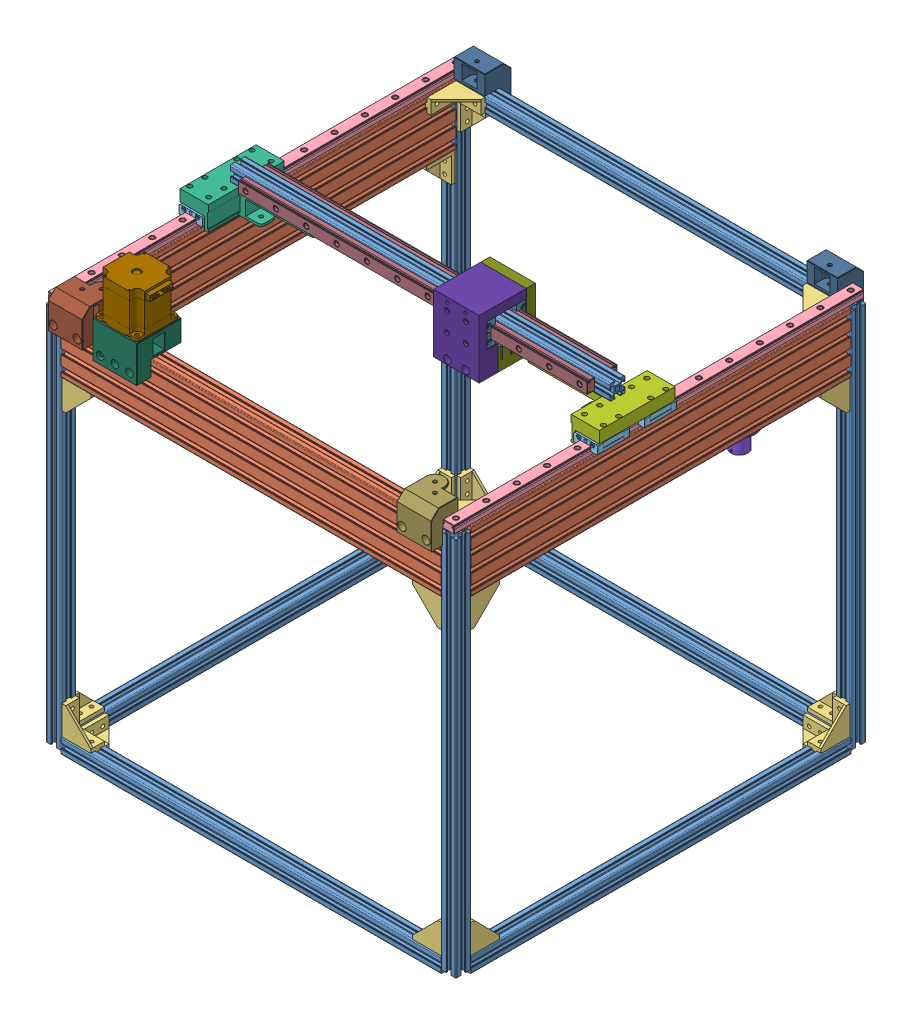
SolidWorks assembly full_assem, configuration Default. Lengths in mm.
Overall size (552 591.02 574.21).
62 component instances, 19 part files, 212 mates.
Components (placement in the parent):
- extrusion_2020_500mm-1: extrusion_2020_500mm [Default] at (57.1895 57.3768 420.5432) size (20 500 20)
- extrusion_2020_500mm-2: extrusion_2020_500mm [Default] at (567.1895 62.3768 420.5432) x (0 1 0) z (0 0 1) size (20 500 20)
- extrusion_2020_500mm-3: extrusion_2020_500mm [Default] at (577.1895 57.3768 420.5432) size (20 500 20)
- extrusion_2020_500mm-6: extrusion_2020_500mm [Default] at (57.1895 57.3768 -99.4568) size (20 500 20)
- extrusion_2020_500mm-7: extrusion_2020_500mm [Default] at (57.1895 62.3768 -89.4568) x (1 0 0) z (0 -1 0) size (20 500 20)
- extrusion_2020_500mm-9: extrusion_2020_500mm [Default] at (577.1895 57.3768 -99.4568) size (20 500 20)
- extrusion_2020_500mm-10: extrusion_2020_500mm [Default] at (577.1895 62.3768 -89.4568) x (1 0 0) z (0 -1 0) size (20 500 20)
- extrusion_2020_500mm-11: extrusion_2020_500mm [Default] at (67.1895 552.3768 -99.4568) x (0 -1 0) z (0 0 1) size (20 500 20)
- extrusion_2020_500mm-12: extrusion_2020_500mm [Default] at (567.1895 62.3768 -99.4568) x (0 1 0) z (0 0 1) size (20 500 20)
- extrusion_2080_500mm-1: extrusion_2080_500mm [Default] at (577.1895 492.3768 -589.4568) size (20 80 500)
- extrusion_2080_500mm-2: extrusion_2080_500mm [Default] at (57.1895 492.3768 -589.4568) size (20 80 500)
- extrusion_2080_500mm-3: extrusion_2080_500mm [Default] at (1067.1895 492.3768 420.5432) x (0 0 1) z (-1 0 0) size (20 80 500)
- corner_2020_38mm-1: corner_2020_38mm [Default] at (567.1895 53.3768 410.5432) x (1 0 0) z (0 1 0) size (40 40 18)
- corner_2020_38mm-3: corner_2020_38mm [Default] at (67.1895 53.3768 410.5432) x (0 0 1) z (0 1 0) size (40 40 18)
- corner_2020_38mm-4: corner_2020_38mm [Default] at (67.1895 53.3768 -89.4568) x (-1 0 0) z (0 1 0) size (40 40 18)
- corner_2020_38mm-5: corner_2020_38mm [Default] at (567.1895 53.3768 -89.4568) x (0 0 -1) z (0 1 0) size (40 40 18)
- corner_2020_38mm-7: corner_2020_38mm [Default] at (48.1895 72.3768 410.5432) x (0 -1 0) z (1 0 0) size (40 40 18)
- corner_2020_38mm-9: corner_2020_38mm [Default] at (48.1895 482.3768 410.5432) x (0 0 1) z (1 0 0) size (40 40 18)
- corner_2020_38mm-10: corner_2020_38mm [Default] at (48.1895 482.3768 -89.4568) x (0 1 0) z (1 0 0) size (40 40 18)
- corner_2020_38mm-11: corner_2020_38mm [Default] at (48.1895 72.3768 -89.4568) x (0 0 -1) z (1 0 0) size (40 40 18)
- corner_2020_38mm-13: corner_2020_38mm [Default] at (67.1895 72.3768 -108.4568) x (0 -1 0) z (0 0 1) size (40 40 18)
- corner_2020_38mm-15: corner_2020_38mm [Default] at (567.1895 72.3768 -108.4568) size (40 40 18)
- corner_2020_38mm-16: corner_2020_38mm [Default] at (567.1895 542.3768 -108.4568) x (0 1 0) z (0 0 1) size (40 40 18)
- corner_2020_38mm-17: corner_2020_38mm [Default] at (67.1895 542.3768 -108.4568) x (-1 0 0) z (0 0 1) size (40 40 18)
- corner_2020_38mm-19: corner_2020_38mm [Default] at (67.1895 561.3768 -89.4568) x (0 0 -1) z (0 -1 0) size (40 40 18)
- corner_2020_38mm-21: corner_2020_38mm [Default] at (567.1895 561.3768 -89.4568) x (1 0 0) z (0 -1 0) size (40 40 18)
- corner_2020_38mm-22: corner_2020_38mm [Default] at (567.1895 561.3768 410.5432) x (0 0 1) z (0 -1 0) size (40 40 18)
- corner_2020_38mm-23: corner_2020_38mm [Default] at (67.1895 561.3768 410.5432) x (-1 0 0) z (0 -1 0) size (40 40 18)
- corner_2020_38mm-25: corner_2020_38mm [Default] at (67.1895 482.3768 429.5432) x (0 1 0) z (0 0 -1) size (40 40 18)
- corner_2020_38mm-27: corner_2020_38mm [Default] at (567.1895 482.3768 429.5432) x (1 0 0) z (0 0 -1) size (40 40 18)
- corner_2020_38mm-28: corner_2020_38mm [Default] at (567.1895 72.3768 429.5432) x (0 -1 0) z (0 0 -1) size (40 40 18)
- corner_2020_38mm-29: corner_2020_38mm [Default] at (67.1895 72.3768 429.5432) x (-1 0 0) z (0 0 -1) size (40 40 18)
- corner_2020_38mm-31: corner_2020_38mm [Default] at (586.1895 72.3768 -89.4568) x (0 -1 0) z (-1 0 0) size (40 40 18)
- corner_2020_38mm-33: corner_2020_38mm [Default] at (586.1895 72.3768 410.5432) x (0 0 1) z (-1 0 0) size (40 40 18)
- corner_2020_38mm-34: corner_2020_38mm [Default] at (586.1895 482.3768 410.5432) x (0 1 0) z (-1 0 0) size (40 40 18)
- corner_2020_38mm-35: corner_2020_38mm [Default] at (586.1895 482.3768 -89.4568) x (0 0 -1) z (-1 0 0) size (40 40 18)
- rail_mgn15_540mm-1: rail_mgn15_540mm [Default] at (57.1895 562.3768 -119.4568) x (0 0 1) z (0 1 0) size (540 15 10)
- rail_mgn15_540mm-2: rail_mgn15_540mm [Default] at (577.1895 562.3768 -119.4568) x (0 0 1) z (0 1 0) size (540 15 10)
- carriage_mgn15c-1: carriage_mgn15c [Default] at (577.1895 562.3768 212.3583) x (0 0 1) z (0 1 0) size (42.1 32 12)
- carriage_mgn15c-2: carriage_mgn15c [Default] at (57.1895 562.3768 212.3583) x (0 0 1) z (0 1 0) size (42.1 32 12)
- bed_400mm-1: bed_400mm [Default] at (317.1895 407.8394 160.5432) size (400 9.53 400) (hidden)
- extrusion_2020_500mm-14: extrusion_2020_500mm [Default] at (67.1895 603.8768 197.8083) x (0 -1 0) z (0 0 1) size (20 500 20)
- carriage_mgn15c-4: carriage_mgn15c [Default] at (577.1895 562.3768 150.2583) x (0 0 1) z (0 1 0) size (42.1 32 12)
- carriage_mgn15c-5: carriage_mgn15c [Default] at (57.1895 562.3768 183.2583) x (0 0 -1) z (0 1 0) size (42.1 32 12)
- brakcet_xy_right-1: brakcet_xy_right [Default] at (41.1895 578.3768 147.8083) x (0 0 1) z (-1 0 0) size (100 31.5 137)
- brakcet_xy_left-1: brakcet_xy_left [Default] at (610.8271 564.0049 199.7363) x (0 0 1) z (-1 0 0) size (100 31.5 137)
- corner_2020_38mm-36: corner_2020_38mm [Default] at (567.1895 483.3768 410.5432) x (1 0 0) z (0 1 0) size (40 40 18)
- corner_2020_38mm-38: corner_2020_38mm [Default] at (67.1895 483.3768 410.5432) x (0 0 1) z (0 1 0) size (40 40 18)
- ballnut_sfu1204-1: ballnut_sfu1204 [Default] at (456.6258 344.4354 -73.2967) size (42.44 40.17 30.1)
- belt_master_model-1: belt_master_model [Default] at (561.1895 566.3768 -109.4568) x (-1 0 0) z (0 0 -1) size (488 0 540)
- motor_stepper_nema23_57mm-2: motor_stepper_nema23_57mm [По умолчанию] at (157.0122 590.3768 420.5432) x (0 0 1) z (0 1 0) size (55 60 79.15)
- belt_end_right-1: belt_end_right [Default] at (84.9257 562.3768 -99.4568) x (-1 0 0) z (0 0 -1) size (40.48 45 35)
- belt_end_right-2: belt_end_right [Default] at (549.4533 562.3768 -99.4568) x (-1 0 0) z (0 0 -1) size (40.48 45 35)
- belt_corner_right-1: belt_corner_right [Default] at (84.9257 562.3768 420.5432) size (45.48 45 50.24)
- belt_corner_left-2: belt_corner_left [Default] at (498.9733 562.3768 420.5432) size (45.48 45 50.24)
- rail_mgn15_460mm-1: rail_mgn15_460mm [Default] at (557.1895 603.8768 187.8083) x (-1 0 0) z (0 0 -1) size (460 15 10)
- carriage_mgn15h-1: carriage_mgn15h [Default] at (415.5036 603.8768 187.8083) x (-1 0 0) z (0 0 -1) size (58.8 32 12)
- stepper_mount_nema23-1: stepper_mount_nema23 [Default] at (157.0122 562.3768 420.5432) x (1 0 0) z (0 1 0) size (58.42 58.42 48)
- belt_mount-1: belt_mount [Default] at (391.0036 593.3768 159.8083) size (60 77 49)
- rail_mgn15_460mm-2: rail_mgn15_460mm [Default] at (77.1895 603.8768 207.8083) size (460 15 10)
- carriage_mgn15h-2: carriage_mgn15h [Default] at (366.5036 603.8768 207.8083) size (58.8 32 12)
- carriage_back-1: carriage_back [Default] at (421.0036 554.8768 233.8083) x (-1 0 0) z (0 -1 0) size (60 62 77)
Mates (geometry in assembly coordinates):
- Distance13: distance = 15 mm anti-aligned: plane of extrusion_2020_500mm-1 through (57.1895 57.3768 420.5432) normal (0 -1 0); plane of extrusion_2020_500mm-2 through (-239.8105 72.3768 420.5432) normal (0 1 0)
- Coincident2: coincident aligned: plane of extrusion_2020_500mm-1 through (57.1895 864.3768 430.5432) normal (0 0 1); plane of extrusion_2020_500mm-2 through (-239.8105 62.3768 430.5432) normal (0 0 1)
- Coincident3: coincident anti-aligned: plane of extrusion_2020_500mm-1 through (67.1895 864.3768 420.5432) normal (1 0 0); plane of extrusion_2020_500mm-2 through (67.1895 62.3768 420.5432) normal (-1 0 0)
- Coincident4: coincident aligned: plane of extrusion_2020_500mm-2 through (-239.8105 62.3768 430.5432) normal (0 0 1); plane of extrusion_2020_500mm-3 through (577.1895 864.3768 430.5432) normal (0 0 1)
- Coincident5: coincident anti-aligned: plane of extrusion_2020_500mm-2 through (567.1895 62.3768 420.5432) normal (1 0 0); plane of extrusion_2020_500mm-3 through (567.1895 864.3768 420.5432) normal (-1 0 0)
- Distance16: distance = 15 mm anti-aligned: plane of extrusion_2020_500mm-2 through (-239.8105 72.3768 420.5432) normal (0 1 0); plane of extrusion_2020_500mm-3 through (577.1895 57.3768 420.5432) normal (0 -1 0)
- Coincident8: coincident anti-aligned: plane of extrusion_2020_500mm-1 through (67.1895 864.3768 420.5432) normal (1 0 0); plane of extrusion_2020_500mm-4 through (67.1895 552.3768 420.5432) normal (-1 0 0)
- Coincident9: coincident aligned: plane of extrusion_2020_500mm-1 through (57.1895 864.3768 430.5432) normal (0 0 1); plane of extrusion_2020_500mm-4 through (-239.8105 552.3768 430.5432) normal (0 0 1)
- Coincident10: coincident anti-aligned: plane of extrusion_2020_500mm-4 through (-239.8105 552.3768 410.5432) normal (0 0 -1); plane of extrusion_2020_500mm-5 through (57.1895 567.3768 410.5432) normal (0 0 1)
- Coincident12: coincident aligned: plane of extrusion_2020_500mm-4 through (-239.8105 562.3768 420.5432) normal (0 1 0); plane of extrusion_2020_500mm-5 through (57.1895 577.3768 717.5432) normal (0 1 0)
- Coincident13: coincident anti-aligned: plane of extrusion_2020_500mm-5 through (57.1895 567.3768 -89.4568) normal (0 0 -1); plane of extrusion_2020_500mm-6 through (57.1895 864.3768 -89.4568) normal (0 0 1)
- Coincident14: coincident anti-aligned: plane of extrusion_2020_500mm-5 through (57.1895 557.3768 717.5432) normal (0 -1 0); plane of extrusion_2020_500mm-6 through (57.1895 557.3768 -99.4568) normal (0 1 0)
- Coincident15: coincident aligned: plane of extrusion_2020_500mm-5 through (47.1895 567.3768 717.5432) normal (-1 0 0); plane of extrusion_2020_500mm-6 through (47.1895 864.3768 -99.4568) normal (-1 0 0)
- Distance14: distance = 15 mm anti-aligned: plane of extrusion_2020_500mm-6 through (57.1895 57.3768 -99.4568) normal (0 -1 0); plane of extrusion_2020_500mm-7 through (57.1895 72.3768 717.5432) normal (0 1 0)
- Coincident17: coincident anti-aligned: plane of extrusion_2020_500mm-1 through (57.1895 864.3768 410.5432) normal (0 0 -1); plane of extrusion_2020_500mm-7 through (57.1895 62.3768 410.5432) normal (0 0 1)
- Coincident18: coincident aligned: plane of extrusion_2020_500mm-1 through (47.1895 864.3768 420.5432) normal (-1 0 0); plane of extrusion_2020_500mm-7 through (47.1895 62.3768 717.5432) normal (-1 0 0)
- Distance15: distance = 15 mm anti-aligned: plane of extrusion_2020_500mm-9 through (577.1895 57.3768 -99.4568) normal (0 -1 0); plane of extrusion_2020_500mm-10 through (577.1895 72.3768 717.5432) normal (0 1 0)
- Coincident26: coincident aligned: plane of extrusion_2020_500mm-9 through (587.1895 864.3768 -99.4568) normal (1 0 0); plane of extrusion_2020_500mm-10 through (587.1895 62.3768 717.5432) normal (1 0 0)
- Coincident27: coincident anti-aligned: plane of extrusion_2020_500mm-9 through (577.1895 864.3768 -89.4568) normal (0 0 1); plane of extrusion_2020_500mm-10 through (577.1895 62.3768 -89.4568) normal (0 0 -1)
- Coincident28: coincident anti-aligned: plane of extrusion_2020_500mm-8 through (577.1895 567.3768 -89.4568) normal (0 0 -1); plane of extrusion_2020_500mm-11 through (874.1895 552.3768 -89.4568) normal (0 0 1)
- Coincident29: coincident anti-aligned: plane of extrusion_2020_500mm-8 through (567.1895 567.3768 717.5432) normal (-1 0 0); plane of extrusion_2020_500mm-11 through (567.1895 552.3768 -99.4568) normal (1 0 0)
- Coincident30: coincident aligned: plane of extrusion_2020_500mm-8 through (577.1895 577.3768 717.5432) normal (0 1 0); plane of extrusion_2020_500mm-11 through (874.1895 562.3768 -99.4568) normal (0 1 0)
- Coincident32: coincident anti-aligned: plane of extrusion_2020_500mm-10 through (577.1895 62.3768 -89.4568) normal (0 0 -1); plane of extrusion_2020_500mm-12 through (-239.8105 62.3768 -89.4568) normal (0 0 1)
- Coincident33: coincident anti-aligned: plane of extrusion_2020_500mm-7 through (67.1895 62.3768 717.5432) normal (1 0 0); plane of extrusion_2020_500mm-12 through (67.1895 62.3768 -99.4568) normal (-1 0 0)
- Coincident34: coincident aligned: plane of extrusion_2020_500mm-2 through (-239.8105 52.3768 420.5432) normal (0 -1 0); plane of corner_2020_38mm-1 through (567.1895 52.3768 410.5432) normal (0 -1 0)
- Coincident35: coincident anti-aligned: plane of extrusion_2020_500mm-10 through (567.1895 62.3768 717.5432) normal (-1 0 0); plane of corner_2020_38mm-1 through (567.1895 71.3768 372.5432) normal (1 0 0)
- Coincident36: coincident anti-aligned: plane of extrusion_2020_500mm-2 through (-239.8105 62.3768 410.5432) normal (0 0 -1); plane of corner_2020_38mm-1 through (567.1895 71.3768 410.5432) normal (0 0 1)
- Coincident40: coincident aligned: plane of extrusion_2020_500mm-2 through (-239.8105 52.3768 420.5432) normal (0 -1 0); plane of corner_2020_38mm-3 through (67.1895 52.3768 410.5432) normal (0 -1 0)
- Coincident41: coincident anti-aligned: plane of extrusion_2020_500mm-2 through (-239.8105 62.3768 410.5432) normal (0 0 -1); plane of corner_2020_38mm-3 through (105.1895 71.3768 410.5432) normal (0 0 1)
- Coincident42: coincident anti-aligned: plane of extrusion_2020_500mm-7 through (67.1895 62.3768 717.5432) normal (1 0 0); plane of corner_2020_38mm-3 through (67.1895 71.3768 410.5432) normal (-1 0 0)
- Coincident43: coincident aligned: plane of extrusion_2020_500mm-2 through (-239.8105 52.3768 420.5432) normal (0 -1 0); plane of corner_2020_38mm-4 through (67.1895 52.3768 -89.4568) normal (0 -1 0)
- Coincident44: coincident anti-aligned: plane of extrusion_2020_500mm-7 through (67.1895 62.3768 717.5432) normal (1 0 0); plane of corner_2020_38mm-4 through (67.1895 71.3768 -51.4568) normal (-1 0 0)
- Coincident45: coincident anti-aligned: plane of extrusion_2020_500mm-12 through (-239.8105 62.3768 -89.4568) normal (0 0 1); plane of corner_2020_38mm-4 through (67.1895 71.3768 -89.4568) normal (0 0 -1)
- Coincident46: coincident aligned: plane of extrusion_2020_500mm-2 through (-239.8105 52.3768 420.5432) normal (0 -1 0); plane of corner_2020_38mm-5 through (567.1895 52.3768 -89.4568) normal (0 -1 0)
- Coincident47: coincident anti-aligned: plane of extrusion_2020_500mm-12 through (-239.8105 62.3768 -89.4568) normal (0 0 1); plane of corner_2020_38mm-5 through (529.1895 71.3768 -89.4568) normal (0 0 -1)
- Coincident48: coincident anti-aligned: plane of extrusion_2020_500mm-10 through (567.1895 62.3768 717.5432) normal (-1 0 0); plane of corner_2020_38mm-5 through (567.1895 71.3768 -89.4568) normal (1 0 0)
- Coincident50: coincident aligned: plane of extrusion_2020_500mm-7 through (47.1895 62.3768 717.5432) normal (-1 0 0); plane of corner_2020_38mm-7 through (47.1895 72.3768 410.5432) normal (-1 0 0)
- Coincident51: coincident anti-aligned: plane of extrusion_2020_500mm-7 through (57.1895 72.3768 717.5432) normal (0 1 0); plane of corner_2020_38mm-7 through (66.1895 72.3768 372.5432) normal (0 -1 0)
- Coincident52: coincident anti-aligned: plane of extrusion_2020_500mm-1 through (57.1895 864.3768 410.5432) normal (0 0 -1); plane of corner_2020_38mm-7 through (66.1895 72.3768 410.5432) normal (0 0 1)
- Coincident53: coincident aligned: plane of extrusion_2020_500mm-7 through (47.1895 62.3768 717.5432) normal (-1 0 0); plane of corner_2020_38mm-9 through (47.1895 482.3768 410.5432) normal (-1 0 0)
- Coincident54: coincident anti-aligned: plane of extrusion_2020_500mm-1 through (57.1895 864.3768 410.5432) normal (0 0 -1); plane of corner_2020_38mm-9 through (66.1895 444.3768 410.5432) normal (0 0 1)
- Coincident56: coincident aligned: plane of extrusion_2020_500mm-7 through (47.1895 62.3768 717.5432) normal (-1 0 0); plane of corner_2020_38mm-10 through (47.1895 482.3768 -89.4568) normal (-1 0 0)
- Coincident58: coincident anti-aligned: plane of extrusion_2020_500mm-6 through (57.1895 864.3768 -89.4568) normal (0 0 1); plane of corner_2020_38mm-10 through (66.1895 482.3768 -89.4568) normal (0 0 -1)
- Coincident59: coincident aligned: plane of extrusion_2020_500mm-7 through (47.1895 62.3768 717.5432) normal (-1 0 0); plane of corner_2020_38mm-11 through (47.1895 72.3768 -89.4568) normal (-1 0 0)
- Coincident60: coincident anti-aligned: plane of extrusion_2020_500mm-6 through (57.1895 864.3768 -89.4568) normal (0 0 1); plane of corner_2020_38mm-11 through (66.1895 110.3768 -89.4568) normal (0 0 -1)
- Coincident61: coincident anti-aligned: plane of extrusion_2020_500mm-7 through (57.1895 72.3768 717.5432) normal (0 1 0); plane of corner_2020_38mm-11 through (66.1895 72.3768 -89.4568) normal (0 -1 0)
- Coincident63: coincident aligned: plane of extrusion_2020_500mm-6 through (57.1895 864.3768 -109.4568) normal (0 0 -1); plane of corner_2020_38mm-13 through (67.1895 72.3768 -109.4568) normal (0 0 -1)
- Coincident64: coincident anti-aligned: plane of extrusion_2020_500mm-12 through (-239.8105 72.3768 -99.4568) normal (0 1 0); plane of corner_2020_38mm-13 through (105.1895 72.3768 -90.4568) normal (0 -1 0)
- Coincident65: coincident anti-aligned: plane of extrusion_2020_500mm-6 through (67.1895 864.3768 -99.4568) normal (1 0 0); plane of corner_2020_38mm-13 through (67.1895 72.3768 -90.4568) normal (-1 0 0)
- Coincident66: coincident aligned: plane of extrusion_2020_500mm-6 through (57.1895 864.3768 -109.4568) normal (0 0 -1); plane of corner_2020_38mm-15 through (567.1895 72.3768 -109.4568) normal (0 0 -1)
- Coincident67: coincident anti-aligned: plane of extrusion_2020_500mm-9 through (567.1895 864.3768 -99.4568) normal (-1 0 0); plane of corner_2020_38mm-15 through (567.1895 110.3768 -90.4568) normal (1 0 0)
- Coincident68: coincident anti-aligned: plane of extrusion_2020_500mm-12 through (-239.8105 72.3768 -99.4568) normal (0 1 0); plane of corner_2020_38mm-15 through (567.1895 72.3768 -90.4568) normal (0 -1 0)
- Coincident69: coincident aligned: plane of extrusion_2020_500mm-6 through (57.1895 864.3768 -109.4568) normal (0 0 -1); plane of corner_2020_38mm-16 through (567.1895 542.3768 -109.4568) normal (0 0 -1)
- Coincident70: coincident anti-aligned: plane of extrusion_2020_500mm-11 through (874.1895 542.3768 -99.4568) normal (0 -1 0); plane of corner_2020_38mm-16 through (529.1895 542.3768 -90.4568) normal (0 1 0)
- Coincident71: coincident anti-aligned: plane of extrusion_2020_500mm-9 through (567.1895 864.3768 -99.4568) normal (-1 0 0); plane of corner_2020_38mm-16 through (567.1895 542.3768 -90.4568) normal (1 0 0)
- Coincident72: coincident aligned: plane of extrusion_2020_500mm-6 through (57.1895 864.3768 -109.4568) normal (0 0 -1); plane of corner_2020_38mm-17 through (67.1895 542.3768 -109.4568) normal (0 0 -1)
- Coincident73: coincident anti-aligned: plane of extrusion_2020_500mm-6 through (67.1895 864.3768 -99.4568) normal (1 0 0); plane of corner_2020_38mm-17 through (67.1895 504.3768 -90.4568) normal (-1 0 0)
- Coincident74: coincident anti-aligned: plane of extrusion_2020_500mm-11 through (874.1895 542.3768 -99.4568) normal (0 -1 0); plane of corner_2020_38mm-17 through (67.1895 542.3768 -90.4568) normal (0 1 0)
- Coincident76: coincident aligned: plane of extrusion_2020_500mm-11 through (874.1895 562.3768 -99.4568) normal (0 1 0); plane of corner_2020_38mm-19 through (67.1895 562.3768 -89.4568) normal (0 1 0)
- Coincident78: coincident anti-aligned: plane of extrusion_2020_500mm-11 through (874.1895 552.3768 -89.4568) normal (0 0 1); plane of corner_2020_38mm-19 through (105.1895 543.3768 -89.4568) normal (0 0 -1)
- Coincident79: coincident anti-aligned: plane of extrusion_2020_500mm-5 through (67.1895 567.3768 717.5432) normal (1 0 0); plane of corner_2020_38mm-19 through (67.1895 543.3768 -89.4568) normal (-1 0 0)
- Coincident80: coincident aligned: plane of extrusion_2020_500mm-11 through (874.1895 562.3768 -99.4568) normal (0 1 0); plane of corner_2020_38mm-21 through (567.1895 562.3768 -89.4568) normal (0 1 0)
- Coincident81: coincident anti-aligned: plane of extrusion_2020_500mm-8 through (567.1895 567.3768 717.5432) normal (-1 0 0); plane of corner_2020_38mm-21 through (567.1895 543.3768 -51.4568) normal (1 0 0)
- Coincident82: coincident anti-aligned: plane of extrusion_2020_500mm-11 through (874.1895 552.3768 -89.4568) normal (0 0 1); plane of corner_2020_38mm-21 through (567.1895 543.3768 -89.4568) normal (0 0 -1)
- Coincident83: coincident aligned: plane of extrusion_2020_500mm-11 through (874.1895 562.3768 -99.4568) normal (0 1 0); plane of corner_2020_38mm-22 through (567.1895 562.3768 410.5432) normal (0 1 0)
- Coincident84: coincident anti-aligned: plane of extrusion_2020_500mm-4 through (-239.8105 552.3768 410.5432) normal (0 0 -1); plane of corner_2020_38mm-22 through (529.1895 543.3768 410.5432) normal (0 0 1)
- Coincident85: coincident anti-aligned: plane of extrusion_2020_500mm-8 through (567.1895 567.3768 717.5432) normal (-1 0 0); plane of corner_2020_38mm-22 through (567.1895 543.3768 410.5432) normal (1 0 0)
- Coincident86: coincident aligned: plane of extrusion_2020_500mm-11 through (874.1895 562.3768 -99.4568) normal (0 1 0); plane of corner_2020_38mm-23 through (67.1895 562.3768 410.5432) normal (0 1 0)
- Coincident87: coincident anti-aligned: plane of extrusion_2020_500mm-5 through (67.1895 567.3768 717.5432) normal (1 0 0); plane of corner_2020_38mm-23 through (67.1895 543.3768 372.5432) normal (-1 0 0)
- Coincident88: coincident anti-aligned: plane of extrusion_2020_500mm-4 through (-239.8105 552.3768 410.5432) normal (0 0 -1); plane of corner_2020_38mm-23 through (67.1895 543.3768 410.5432) normal (0 0 1)
- Coincident90: coincident aligned: plane of extrusion_2020_500mm-1 through (57.1895 864.3768 430.5432) normal (0 0 1); plane of corner_2020_38mm-25 through (67.1895 482.3768 430.5432) normal (0 0 1)
- Coincident92: coincident anti-aligned: plane of extrusion_2020_500mm-4 through (-239.8105 542.3768 420.5432) normal (0 -1 0); plane of corner_2020_38mm-25 through (105.1895 482.3768 411.5432) normal (0 1 0)
- Coincident93: coincident anti-aligned: plane of extrusion_2020_500mm-1 through (67.1895 864.3768 420.5432) normal (1 0 0); plane of corner_2020_38mm-25 through (67.1895 482.3768 411.5432) normal (-1 0 0)
- Coincident94: coincident aligned: plane of extrusion_2020_500mm-1 through (57.1895 864.3768 430.5432) normal (0 0 1); plane of corner_2020_38mm-27 through (567.1895 482.3768 430.5432) normal (0 0 1)
- Coincident95: coincident anti-aligned: plane of extrusion_2020_500mm-3 through (567.1895 864.3768 420.5432) normal (-1 0 0); plane of corner_2020_38mm-27 through (567.1895 444.3768 411.5432) normal (1 0 0)
- Coincident96: coincident anti-aligned: plane of extrusion_2020_500mm-4 through (-239.8105 542.3768 420.5432) normal (0 -1 0); plane of corner_2020_38mm-27 through (567.1895 482.3768 411.5432) normal (0 1 0)
- Coincident97: coincident aligned: plane of extrusion_2020_500mm-1 through (57.1895 864.3768 430.5432) normal (0 0 1); plane of corner_2020_38mm-28 through (567.1895 72.3768 430.5432) normal (0 0 1)
- Coincident98: coincident anti-aligned: plane of extrusion_2020_500mm-2 through (-239.8105 72.3768 420.5432) normal (0 1 0); plane of corner_2020_38mm-28 through (529.1895 72.3768 411.5432) normal (0 -1 0)
- Coincident99: coincident anti-aligned: plane of extrusion_2020_500mm-3 through (567.1895 864.3768 420.5432) normal (-1 0 0); plane of corner_2020_38mm-28 through (567.1895 72.3768 411.5432) normal (1 0 0)
- Coincident100: coincident aligned: plane of extrusion_2020_500mm-1 through (57.1895 864.3768 430.5432) normal (0 0 1); plane of corner_2020_38mm-29 through (67.1895 72.3768 430.5432) normal (0 0 1)
- Coincident101: coincident anti-aligned: plane of extrusion_2020_500mm-1 through (67.1895 864.3768 420.5432) normal (1 0 0); plane of corner_2020_38mm-29 through (67.1895 110.3768 411.5432) normal (-1 0 0)
- Coincident102: coincident anti-aligned: plane of extrusion_2020_500mm-2 through (-239.8105 72.3768 420.5432) normal (0 1 0); plane of corner_2020_38mm-29 through (67.1895 72.3768 411.5432) normal (0 -1 0)
- Coincident104: coincident aligned: plane of extrusion_2020_500mm-10 through (587.1895 62.3768 717.5432) normal (1 0 0); plane of corner_2020_38mm-31 through (587.1895 72.3768 -89.4568) normal (1 0 0)
- Coincident105: coincident anti-aligned: plane of extrusion_2020_500mm-10 through (577.1895 72.3768 717.5432) normal (0 1 0); plane of corner_2020_38mm-31 through (568.1895 72.3768 -51.4568) normal (0 -1 0)
- Coincident106: coincident anti-aligned: plane of extrusion_2020_500mm-9 through (577.1895 864.3768 -89.4568) normal (0 0 1); plane of corner_2020_38mm-31 through (568.1895 72.3768 -89.4568) normal (0 0 -1)
- Coincident107: coincident aligned: plane of extrusion_2020_500mm-10 through (587.1895 62.3768 717.5432) normal (1 0 0); plane of corner_2020_38mm-33 through (587.1895 72.3768 410.5432) normal (1 0 0)
- Coincident108: coincident anti-aligned: plane of extrusion_2020_500mm-3 through (577.1895 864.3768 410.5432) normal (0 0 -1); plane of corner_2020_38mm-33 through (568.1895 110.3768 410.5432) normal (0 0 1)
- Coincident109: coincident anti-aligned: plane of extrusion_2020_500mm-10 through (577.1895 72.3768 717.5432) normal (0 1 0); plane of corner_2020_38mm-33 through (568.1895 72.3768 410.5432) normal (0 -1 0)
- Coincident110: coincident aligned: plane of extrusion_2020_500mm-10 through (587.1895 62.3768 717.5432) normal (1 0 0); plane of corner_2020_38mm-34 through (587.1895 482.3768 410.5432) normal (1 0 0)
- Coincident112: coincident anti-aligned: plane of extrusion_2020_500mm-3 through (577.1895 864.3768 410.5432) normal (0 0 -1); plane of corner_2020_38mm-34 through (568.1895 482.3768 410.5432) normal (0 0 1)
- Coincident113: coincident aligned: plane of extrusion_2020_500mm-10 through (587.1895 62.3768 717.5432) normal (1 0 0); plane of corner_2020_38mm-35 through (587.1895 482.3768 -89.4568) normal (1 0 0)
- Coincident114: coincident anti-aligned: plane of extrusion_2020_500mm-9 through (577.1895 864.3768 -89.4568) normal (0 0 1); plane of corner_2020_38mm-35 through (568.1895 444.3768 -89.4568) normal (0 0 -1)
- Coincident118: coincident anti-aligned: plane of extrusion_2080_500mm-2 through (67.1895 562.3768 -589.4568) normal (0 1 0); plane of rail_mgn15_540mm-1 through (49.6895 562.3768 -119.4568) normal (0 -1 0)
- Coincident120: coincident aligned: plane of extrusion_2020_500mm-1 through (57.1895 864.3768 430.5432) normal (0 0 1); plane of rail_mgn15_540mm-1 through (57.1895 562.3768 430.5432) normal (0 0 1)
- Coincident121: coincident anti-aligned: plane of extrusion_2020_500mm-8 through (577.1895 577.3768 717.5432) normal (0 1 0); plane of rail_mgn15_540mm-2 through (569.6895 562.3768 -119.4568) normal (0 -1 0)
- Distance2: distance = 2.5 mm aligned: plane of rail_mgn15_540mm-2 through (584.6895 562.3768 -119.4568) normal (1 0 0); plane of extrusion_2020_500mm-8 through (587.1895 567.3768 717.5432) normal (1 0 0)
- Coincident122: coincident aligned: plane of extrusion_2020_500mm-3 through (577.1895 864.3768 430.5432) normal (0 0 1); plane of rail_mgn15_540mm-2 through (577.1895 562.3768 430.5432) normal (0 0 1)
- Coincident123: coincident anti-aligned: plane of rail_mgn15_540mm-2 through (584.6895 572.3768 -119.4568) normal (0 1 0); plane of carriage_mgn15c-1 through (570.1895 572.3768 215.5083) normal (0 -1 0)
- Coincident124: coincident anti-aligned: plane of rail_mgn15_540mm-2 through (569.6895 572.3768 -119.4568) normal (-1 0 0); plane of carriage_mgn15c-1 through (569.6895 570.926 209.8083) normal (1 0 0)
- Coincident125: coincident anti-aligned: plane of rail_mgn15_540mm-1 through (64.6895 572.3768 -119.4568) normal (0 1 0); plane of carriage_mgn15c-2 through (50.1895 572.3768 215.5083) normal (0 -1 0)
- Coincident126: coincident anti-aligned: plane of rail_mgn15_540mm-1 through (49.6895 572.3768 -119.4568) normal (-1 0 0); plane of carriage_mgn15c-2 through (49.6895 570.926 209.8083) normal (1 0 0)
- Coincident127: coincident aligned: plane of carriage_mgn15c-1 through (577.1895 572.1117 207.8083) normal (0 0 -1); plane of carriage_mgn15c-2 through (57.1895 572.1117 207.8083) normal (0 0 -1)
- Coincident128: coincident anti-aligned: plane of bed_400mm-1 through (317.1895 407.8394 160.5432) normal (1 0 0)
- Coincident129: coincident anti-aligned: plane of bed_400mm-1 through (317.1895 407.8394 160.5432) normal (0 0 1)
- Coincident130: coincident anti-aligned: plane of carriage_mgn15c-1 through (577.1895 572.1117 207.8083) normal (0 0 -1); plane of extrusion_2020_500mm-14 through (874.1895 603.8768 207.8083) normal (0 0 1)
- Coincident133: coincident aligned: plane of carriage_mgn15c-1 through (593.1895 577.5768 215.5083) normal (1 0 0); plane of carriage_mgn15c-4 through (593.1895 577.5768 153.4083) normal (1 0 0)
- Coincident134: coincident aligned: plane of carriage_mgn15c-1 through (585.1895 578.3768 215.5083) normal (0 1 0); plane of carriage_mgn15c-4 through (585.1895 578.3768 153.4083) normal (0 1 0)
- Coincident135: coincident anti-aligned: plane of extrusion_2020_500mm-14 through (874.1895 603.8768 187.8083) normal (0 0 -1); plane of carriage_mgn15c-4 through (577.1895 572.1117 187.8083) normal (0 0 1)
- Coincident136: coincident aligned: plane of carriage_mgn15c-2 through (41.9895 578.3768 215.5083) normal (0 1 0); plane of carriage_mgn15c-5 through (72.3895 578.3768 180.1083) normal (0 1 0)
- Coincident137: coincident aligned: plane of carriage_mgn15c-2 through (41.1895 567.1768 215.5083) normal (-1 0 0); plane of carriage_mgn15c-5 through (41.1895 577.5768 180.1083) normal (-1 0 0)
- Coincident138: coincident anti-aligned: plane of extrusion_2020_500mm-14 through (874.1895 603.8768 187.8083) normal (0 0 -1); plane of carriage_mgn15c-5 through (57.1895 572.1117 187.8083) normal (0 0 1)
- Coincident141: coincident anti-aligned: plane of carriage_mgn15c-5 through (49.1895 578.3768 180.1083) normal (0 1 0); plane of brakcet_xy_right-1 through (41.1895 578.3768 147.8083) normal (0 -1 0)
- Coincident142: coincident aligned: plane of extrusion_2020_500mm-14 through (67.1895 603.8768 197.8083) normal (0 0 1); plane of brakcet_xy_right-1 through (41.1895 578.3768 197.8083) normal (0 0 1)
- Coincident143: coincident aligned: plane of carriage_mgn15c-5 through (57.1895 562.3768 183.2583) normal (-1 0 0); plane of brakcet_xy_right-1 through (57.1895 578.3768 147.8083) normal (-1 0 0)
- Coincident147: coincident aligned: plane of extrusion_2020_500mm-3 through (587.1895 864.3768 420.5432) normal (1 0 0); plane of extrusion_2080_500mm-1 through (587.1895 495.9768 -589.4568) normal (1 0 0)
- Coincident148: coincident aligned: plane of extrusion_2020_500mm-4 through (-239.8105 562.3768 420.5432) normal (0 1 0); plane of extrusion_2080_500mm-1 through (573.5895 562.3768 -589.4568) normal (0 1 0)
- Coincident149: coincident anti-aligned: plane of extrusion_2020_500mm-3 through (577.1895 864.3768 410.5432) normal (0 0 -1); plane of extrusion_2080_500mm-1 through (577.1895 522.3768 410.5432) normal (0 0 1)
- Coincident150: coincident aligned: plane of extrusion_2020_500mm-3 through (587.1895 864.3768 420.5432) normal (1 0 0); plane of extrusion_2020_500mm-9 through (587.1895 864.3768 -99.4568) normal (1 0 0)
- Coincident151: coincident anti-aligned: plane of extrusion_2020_500mm-9 through (577.1895 864.3768 -89.4568) normal (0 0 1); plane of extrusion_2080_500mm-1 through (577.1895 492.3768 -89.4568) normal (0 0 -1)
- Coincident152: coincident anti-aligned: plane of corner_2020_38mm-35 through (568.1895 482.3768 -89.4568) normal (0 1 0); plane of extrusion_2080_500mm-1 through (567.1895 482.3768 -589.4568) normal (0 -1 0)
- Coincident153: coincident anti-aligned: plane of corner_2020_38mm-34 through (568.1895 482.3768 372.5432) normal (0 1 0); plane of extrusion_2080_500mm-1 through (567.1895 482.3768 -589.4568) normal (0 -1 0)
- Distance4: distance = 5 mm aligned: plane of extrusion_2020_500mm-9 through (577.1895 557.3768 -99.4568) normal (0 1 0); plane of extrusion_2080_500mm-1 through (587.1895 562.3768 -589.4568) normal (0 1 0)
- Distance6: distance = 5 mm aligned: plane of extrusion_2020_500mm-3 through (577.1895 557.3768 420.5432) normal (0 1 0); plane of extrusion_2020_500mm-4 through (-239.8105 562.3768 420.5432) normal (0 1 0)
- Coincident156: coincident aligned: plane of extrusion_2020_500mm-6 through (57.1895 864.3768 -109.4568) normal (0 0 -1); plane of extrusion_2020_500mm-11 through (874.1895 552.3768 -109.4568) normal (0 0 -1)
- Coincident158: coincident aligned: plane of extrusion_2020_500mm-9 through (577.1895 864.3768 -109.4568) normal (0 0 -1); plane of extrusion_2020_500mm-11 through (874.1895 552.3768 -109.4568) normal (0 0 -1)
- Coincident159: coincident anti-aligned: plane of extrusion_2020_500mm-9 through (567.1895 864.3768 -99.4568) normal (-1 0 0); plane of extrusion_2020_500mm-11 through (567.1895 552.3768 -99.4568) normal (1 0 0)
- Distance7: distance = 5 mm aligned: plane of extrusion_2020_500mm-9 through (577.1895 557.3768 -99.4568) normal (0 1 0); plane of extrusion_2020_500mm-11 through (874.1895 562.3768 -99.4568) normal (0 1 0)
- Coincident161: coincident aligned: plane of extrusion_2020_500mm-6 through (47.1895 864.3768 -99.4568) normal (-1 0 0); plane of extrusion_2080_500mm-2 through (47.1895 528.7768 -589.4568) normal (-1 0 0)
- Coincident162: coincident anti-aligned: plane of extrusion_2020_500mm-6 through (57.1895 864.3768 -89.4568) normal (0 0 1); plane of extrusion_2080_500mm-2 through (57.1895 492.3768 -89.4568) normal (0 0 -1)
- Coincident163: coincident aligned: plane of extrusion_2020_500mm-11 through (874.1895 562.3768 -99.4568) normal (0 1 0); plane of extrusion_2080_500mm-2 through (53.5895 562.3768 -589.4568) normal (0 1 0)
- Coincident164: coincident anti-aligned: plane of extrusion_2020_500mm-6 through (67.1895 864.3768 -99.4568) normal (1 0 0); plane of extrusion_2020_500mm-11 through (67.1895 552.3768 -99.4568) normal (-1 0 0)
- Coincident165: coincident aligned: plane of extrusion_2080_500mm-2 through (67.1895 562.3768 -589.4568) normal (0 1 0); plane of extrusion_2080_500mm-3 through (1067.1895 562.3768 416.9432) normal (0 1 0)
- Coincident166: coincident aligned: plane of extrusion_2020_500mm-1 through (57.1895 864.3768 430.5432) normal (0 0 1); plane of extrusion_2080_500mm-3 through (1067.1895 535.9768 430.5432) normal (0 0 1)
- Coincident167: coincident anti-aligned: plane of extrusion_2020_500mm-1 through (67.1895 864.3768 420.5432) normal (1 0 0); plane of extrusion_2080_500mm-3 through (67.1895 522.3768 420.5432) normal (-1 0 0)
- Coincident168: coincident anti-aligned: plane of corner_2020_38mm-25 through (105.1895 482.3768 411.5432) normal (0 1 0); plane of extrusion_2080_500mm-3 through (1067.1895 482.3768 424.1432) normal (0 -1 0)
- Distance8: distance = 5 mm aligned: plane of extrusion_2080_500mm-3 through (1067.1895 562.3768 416.9432) normal (0 1 0); plane of extrusion_2020_500mm-1 through (57.1895 557.3768 420.5432) normal (0 1 0)
- Coincident171: coincident anti-aligned: plane of corner_2020_38mm-9 through (66.1895 482.3768 410.5432) normal (0 1 0); plane of extrusion_2080_500mm-2 through (60.7895 482.3768 -589.4568) normal (0 -1 0)
- Coincident172: coincident anti-aligned: plane of corner_2020_38mm-27 through (567.1895 482.3768 411.5432) normal (0 1 0); plane of extrusion_2080_500mm-3 through (1067.1895 482.3768 410.5432) normal (0 -1 0)
- Distance9: distance = 5 mm aligned: plane of extrusion_2020_500mm-6 through (57.1895 557.3768 -99.4568) normal (0 1 0); plane of extrusion_2080_500mm-2 through (53.5895 562.3768 -589.4568) normal (0 1 0)
- Coincident174: coincident anti-aligned: plane of corner_2020_38mm-10 through (66.1895 482.3768 -51.4568) normal (0 1 0); plane of extrusion_2080_500mm-2 through (60.7895 482.3768 -589.4568) normal (0 -1 0)
- Distance10: distance = 10 mm anti-aligned: plane of rail_mgn15_540mm-1 through (57.1895 562.3768 -119.4568) normal (1 0 0); plane of extrusion_2080_500mm-2 through (47.1895 548.7768 -589.4568) normal (-1 0 0)
- Coincident175: coincident anti-aligned: plane of rail_mgn15_540mm-2 through (569.6895 562.3768 -119.4568) normal (0 -1 0); plane of extrusion_2080_500mm-1 through (573.5895 562.3768 -589.4568) normal (0 1 0)
- Distance11: distance = 2.5 mm aligned: plane of rail_mgn15_540mm-2 through (584.6895 562.3768 -119.4568) normal (1 0 0); plane of extrusion_2080_500mm-1 through (587.1895 555.9768 -589.4568) normal (1 0 0)
- Coincident178: coincident aligned: plane of extrusion_2020_500mm-7 through (57.1895 52.3768 717.5432) normal (0 -1 0); plane of extrusion_2020_500mm-12 through (-239.8105 52.3768 -99.4568) normal (0 -1 0)
- Coincident179: coincident aligned: plane of extrusion_2080_500mm-1 through (567.1895 482.3768 -589.4568) normal (0 -1 0); plane of corner_2020_38mm-36 through (567.1895 482.3768 410.5432) normal (0 -1 0)
- Coincident180: coincident anti-aligned: plane of extrusion_2080_500mm-1 through (567.1895 508.7768 -589.4568) normal (-1 0 0); plane of corner_2020_38mm-36 through (567.1895 501.3768 372.5432) normal (1 0 0)
- Coincident181: coincident anti-aligned: plane of extrusion_2080_500mm-3 through (1067.1895 508.7768 410.5432) normal (0 0 -1); plane of corner_2020_38mm-36 through (567.1895 501.3768 410.5432) normal (0 0 1)
- Coincident182: coincident aligned: plane of extrusion_2080_500mm-3 through (1067.1895 482.3768 424.1432) normal (0 -1 0); plane of corner_2020_38mm-38 through (67.1895 482.3768 410.5432) normal (0 -1 0)
- Coincident183: coincident anti-aligned: plane of extrusion_2080_500mm-3 through (1067.1895 508.7768 410.5432) normal (0 0 -1); plane of corner_2020_38mm-38 through (105.1895 501.3768 410.5432) normal (0 0 1)
- Coincident184: coincident anti-aligned: plane of extrusion_2080_500mm-2 through (67.1895 495.9768 -589.4568) normal (1 0 0); plane of corner_2020_38mm-38 through (67.1895 501.3768 410.5432) normal (-1 0 0)
- Coincident187: coincident anti-aligned: plane of brakcet_xy_left-1 through (561.1895 462.2519 147.8083) normal (1 0 0); plane of carriage_mgn15c-4 through (561.1895 567.1768 153.4083) normal (-1 0 0)
- Coincident188: coincident aligned: plane of brakcet_xy_right-1 through (41.1895 584.3768 247.8083) normal (0 0 1); plane of brakcet_xy_left-1 through (593.1895 584.3768 247.8083) normal (0 0 1)
- Coincident189: coincident anti-aligned: plane of brakcet_xy_left-1 through (593.1895 578.3768 147.8083) normal (0 -1 0); plane of carriage_mgn15c-4 through (585.1895 578.3768 153.4083) normal (0 1 0)
- Distance17: distance = 4 mm aligned: plane of extrusion_2080_500mm-3 through (1067.1895 562.3768 430.5432) normal (0 1 0); plane of belt_master_model-1 through (561.1895 566.3768 -109.4568) normal (0 1 0)
- Coincident194: coincident aligned: plane of carriage_mgn15c-4 through (561.1895 567.1768 153.4083) normal (-1 0 0); plane of belt_master_model-1 through (561.1895 566.3768 -109.4568) normal (-1 0 0)
- Coincident195: coincident aligned: plane of extrusion_2020_500mm-11 through (874.1895 552.3768 -109.4568) normal (0 0 -1); plane of belt_master_model-1 through (561.1895 566.3768 -109.4568) normal (0 0 -1)
- Concentric1: concentric anti-aligned: circle of belt_master_model-1; cylinder of motor_stepper_nema23_57mm-1 through (487.9895 588.3768 382.3432) axis (0 -1 0) radius 4
- Coincident196: coincident aligned: plane of extrusion_2080_500mm-3 through (1067.1895 562.3768 430.5432) normal (0 1 0); plane of motor_stepper_nema23_57mm-1 through (487.9895 562.3768 382.3432) normal (0 1 0)
- Parallel1: parallel anti-aligned: plane of extrusion_2080_500mm-3 through (1067.1895 548.7768 410.5432) normal (0 0 -1); plane of motor_stepper_nema23_57mm-1 through (487.9895 558.3768 409.8432) normal (0 0 1)
- Coincident201: coincident anti-aligned: plane of extrusion_2020_500mm-11 through (874.1895 562.3768 -99.4568) normal (0 1 0); plane of belt_end_right-1 through (84.9257 562.3768 -99.4568) normal (0 -1 0)
- Coincident203: coincident aligned: plane of extrusion_2020_500mm-11 through (874.1895 552.3768 -109.4568) normal (0 0 -1); plane of belt_end_left-1 through (479.8233 577.3768 -109.4568) normal (0 0 -1)
- Coincident204: coincident anti-aligned: plane of extrusion_2020_500mm-11 through (874.1895 562.3768 -99.4568) normal (0 1 0); plane of belt_end_left-1 through (549.8233 562.3768 -99.4568) normal (0 -1 0)
- Concentric5: concentric: point of belt_master_model-1; cylinder of belt_end_right-1 through (84.9257 587.3768 -99.4568) axis (0 -1 0) radius 2.5
- Coincident205: coincident anti-aligned: plane of extrusion_2080_500mm-3 through (1067.1895 562.3768 430.5432) normal (0 1 0); plane of belt_corner_left-1 through (459.6895 562.3768 430.5432) normal (0 -1 0)
- Coincident206: coincident anti-aligned: plane of rail_mgn15_540mm-2 through (569.6895 568.1434 -119.4568) normal (-1 0 0); plane of belt_corner_left-1 through (569.6895 577.3768 430.5432) normal (1 0 0)
- Coincident207: coincident aligned: plane of extrusion_2080_500mm-3 through (1067.1895 555.9768 430.5432) normal (0 0 1); plane of belt_corner_left-1 through (459.6895 577.3768 430.5432) normal (0 0 1)
- Coincident208: coincident anti-aligned: plane of extrusion_2020_500mm-11 through (874.1895 552.3768 -109.4568) normal (0 0 -1); plane of belt_end_right-1 through (84.9257 562.3768 -109.4568) normal (0 0 1)
- Concentric9: concentric: point of belt_master_model-1; cylinder of belt_end_right-2 through (549.4533 587.3768 -99.4568) axis (0 -1 0) radius 2.5
- Coincident210: coincident anti-aligned: plane of extrusion_2020_500mm-11 through (874.1895 562.3768 -99.4568) normal (0 1 0); plane of belt_end_right-2 through (549.4533 562.3768 -99.4568) normal (0 -1 0)
- Coincident211: coincident anti-aligned: plane of extrusion_2020_500mm-11 through (874.1895 552.3768 -109.4568) normal (0 0 -1); plane of belt_end_right-2 through (549.4533 562.3768 -109.4568) normal (0 0 1)
- Coincident212: coincident anti-aligned: plane of extrusion_2080_500mm-3 through (1067.1895 535.9768 430.5432) normal (0 0 1); plane of belt_corner_right-1 through (84.9257 562.3768 430.5432) normal (0 0 -1)
- Coincident213: coincident anti-aligned: plane of extrusion_2080_500mm-3 through (1067.1895 562.3768 430.5432) normal (0 1 0); plane of belt_corner_right-1 through (84.9257 562.3768 420.5432) normal (0 -1 0)
- Concentric7: concentric: point of belt_master_model-1; cylinder of belt_corner_right-1 through (84.9257 587.3768 420.5432) axis (0 -1 0) radius 2.5
- Coincident215: coincident anti-aligned: plane of extrusion_2080_500mm-3 through (1067.1895 535.9768 430.5432) normal (0 0 1); plane of belt_corner_left-2 through (549.4533 562.3768 430.5432) normal (0 0 -1)
- Coincident216: coincident anti-aligned: plane of extrusion_2080_500mm-3 through (1067.1895 562.3768 430.5432) normal (0 1 0); plane of belt_corner_left-2 through (549.4533 562.3768 420.5432) normal (0 -1 0)
- Concentric8: concentric: point of belt_master_model-1; cylinder of belt_corner_left-2 through (549.4533 587.3768 420.5432) axis (0 -1 0) radius 2.5
- Coincident218: coincident aligned: plane of motor_stepper_nema23_57mm-1 through (487.9895 562.3768 382.3432) normal (0 1 0); plane of motor_stepper_nema23_57mm-3 through (421.5895 562.3768 382.3432) normal (0 1 0)
- Concentric10: concentric anti-aligned: circle of belt_master_model-1; cylinder of motor_stepper_nema23_57mm-3 through (421.5895 588.3768 382.3432) axis (0 -1 0) radius 4
- Parallel3: parallel anti-aligned: plane of extrusion_2080_500mm-3 through (1067.1895 548.7768 410.5432) normal (0 0 -1); plane of motor_stepper_nema23_57mm-3 through (421.5895 558.3768 409.8432) normal (0 0 1)
- Coincident220: coincident anti-aligned: plane of extrusion_2080_500mm-3 through (1067.1895 562.3768 430.5432) normal (0 1 0); plane of mount_motor_left-1 through (487.9895 562.3768 382.3432) normal (0 -1 0)
- Coincident221: coincident anti-aligned: plane of extrusion_2080_500mm-3 through (1067.1895 535.9768 430.5432) normal (0 0 1); plane of mount_motor_left-1 through (516.1895 542.3768 430.5432) normal (0 0 -1)
- Coincident223: coincident: line of belt_master_model-1 through (516.1895 566.3768 410.5432) axis (0 0 -1); plane of mount_motor_left-1 through (516.1895 587.3768 410.5432) normal (1 0 0)
- Concentric11: concentric anti-aligned: cylinder of motor_stepper_nema23_57mm-3 through (421.5895 588.3768 382.3432) axis (0 -1 0) radius 4; cylinder of mount_motor_left-2 through (421.5895 542.3768 382.3432) axis (0 1 0) radius 19.05
- Coincident224: coincident anti-aligned: plane of extrusion_2080_500mm-3 through (1067.1895 562.3768 430.5432) normal (0 1 0); plane of mount_motor_left-2 through (421.5895 562.3768 382.3432) normal (0 -1 0)
- Coincident225: coincident anti-aligned: plane of extrusion_2080_500mm-3 through (1067.1895 535.9768 430.5432) normal (0 0 1); plane of mount_motor_left-2 through (449.7895 542.3768 430.5432) normal (0 0 -1)
- Coincident226: coincident anti-aligned: plane of extrusion_2080_500mm-3 through (1067.1895 562.3768 430.5432) normal (0 1 0); plane of mount_motor_right-1 through (146.3895 562.3768 382.3432) normal (0 -1 0)
- Coincident227: coincident anti-aligned: plane of extrusion_2080_500mm-3 through (1067.1895 535.9768 430.5432) normal (0 0 1); plane of mount_motor_right-1 through (118.1895 542.3768 430.5432) normal (0 0 -1)
- Coincident228: coincident anti-aligned: plane of extrusion_2020_500mm-14 through (874.1895 603.8768 187.8083) normal (0 0 -1); plane of rail_mgn15_460mm-1 through (557.1895 596.3768 187.8083) normal (0 0 1)
- Coincident229: coincident anti-aligned: plane of extrusion_2020_500mm-14 through (67.1895 603.8768 197.8083) normal (0 -1 0); plane of rail_mgn15_460mm-1 through (557.1895 603.8768 187.8083) normal (0 1 0)
- Distance18: distance = 20 mm aligned: plane of rail_mgn15_460mm-1 through (547.1895 603.8768 187.8083) normal (1 0 0); plane of extrusion_2020_500mm-14 through (567.1895 603.8768 197.8083) normal (1 0 0)
- Coincident231: coincident anti-aligned: plane of extrusion_2080_500mm-1 through (567.1895 548.7768 -589.4568) normal (-1 0 0); plane of extrusion_2020_500mm-14 through (567.1895 603.8768 197.8083) normal (1 0 0)
- Coincident233: coincident anti-aligned: plane of extrusion_2020_500mm-14 through (874.1895 593.8768 197.8083) normal (0 -1 0); plane of brakcet_xy_left-1 through (593.1895 593.8768 147.8083) normal (0 1 0)
- Coincident234: coincident anti-aligned: plane of rail_mgn15_460mm-1 through (557.1895 611.3768 177.8083) normal (0 0 -1); plane of carriage_mgn15h-1 through (412.7036 596.8768 177.8083) normal (0 0 1)
- Coincident235: coincident anti-aligned: plane of rail_mgn15_460mm-1 through (557.1895 596.3768 177.8083) normal (0 -1 0); plane of carriage_mgn15h-1 through (363.6036 596.3768 178.3083) normal (0 1 0)
- Concentric13: concentric: point of belt_master_model-1; cylinder of motor_stepper_nema23_57mm-2 through (157.0122 564.3768 420.5432) axis (0 1 0) radius 4
- Distance20: distance = 28 mm anti-aligned: plane of motor_stepper_nema23_57mm-2 through (157.0122 590.3768 420.5432) normal (0 -1 0); plane of extrusion_2080_500mm-3 through (1067.1895 562.3768 416.9432) normal (0 1 0)
- Parallel4: parallel aligned: plane of extrusion_2080_500mm-3 through (1067.1895 555.9768 430.5432) normal (0 0 1); plane of motor_stepper_nema23_57mm-2 through (157.0122 632.3868 448.0432) normal (0 0 1)
- Coincident239: coincident anti-aligned: plane of extrusion_2080_500mm-3 through (1067.1895 535.9768 430.5432) normal (0 0 1); plane of stepper_mount_nema23-1 through (127.8022 542.3768 430.5432) normal (0 0 -1)
- Coincident240: coincident anti-aligned: plane of extrusion_2080_500mm-3 through (1067.1895 562.3768 416.9432) normal (0 1 0); plane of stepper_mount_nema23-1 through (157.0122 562.3768 420.5432) normal (0 -1 0)
- Concentric14: concentric aligned: cylinder of motor_stepper_nema23_57mm-2 through (157.0122 564.3768 420.5432) axis (0 1 0) radius 4; cylinder of stepper_mount_nema23-1 through (157.0122 542.3768 420.5432) axis (0 1 0) radius 10
- Coincident241: coincident aligned: plane of carriage_mgn15h-1 through (412.7036 619.8768 172.6083) normal (0 1 0); plane of belt_mount-1 through (391.0036 619.8768 159.8083) normal (0 1 0)
- Coincident242: coincident anti-aligned: plane of carriage_mgn15h-1 through (391.0036 603.8768 187.8083) normal (-1 0 0); plane of belt_mount-1 through (391.0036 593.3768 159.8083) normal (1 0 0)
- Coincident243: coincident anti-aligned: plane of carriage_mgn15h-1 through (412.7036 611.8768 171.8083) normal (0 0 -1); plane of belt_mount-1 through (391.0036 593.3768 171.8083) normal (0 0 1)
- Coincident244: coincident aligned: plane of rail_mgn15_460mm-1 through (87.1895 603.8768 187.8083) normal (-1 0 0); plane of rail_mgn15_460mm-2 through (87.1895 603.8768 207.8083) normal (-1 0 0)
- Coincident245: coincident anti-aligned: plane of extrusion_2020_500mm-14 through (874.1895 603.8768 207.8083) normal (0 0 1); plane of rail_mgn15_460mm-2 through (77.1895 596.3768 207.8083) normal (0 0 -1)
- Coincident246: coincident aligned: plane of rail_mgn15_460mm-1 through (557.1895 611.3768 187.8083) normal (0 1 0); plane of rail_mgn15_460mm-2 through (77.1895 611.3768 207.8083) normal (0 1 0)
- Coincident247: coincident aligned: plane of carriage_mgn15h-1 through (412.7036 619.8768 179.2083) normal (0 1 0); plane of carriage_mgn15h-2 through (369.3036 619.8768 223.0083) normal (0 1 0)
- Coincident248: coincident aligned: plane of carriage_mgn15h-1 through (361.6036 603.8768 178.0734) normal (-1 0 0); plane of carriage_mgn15h-2 through (361.6036 603.8768 217.5432) normal (-1 0 0)
- Coincident249: coincident anti-aligned: plane of rail_mgn15_460mm-2 through (77.1895 611.3768 217.8083) normal (0 0 1); plane of carriage_mgn15h-2 through (363.6036 596.8768 217.8083) normal (0 0 -1)
- Coincident250: coincident anti-aligned: plane of carriage_mgn15h-2 through (369.3036 619.8768 216.4083) normal (0 1 0); plane of carriage_back-1 through (421.0036 619.8768 171.8083) normal (0 -1 0)
- Coincident251: coincident anti-aligned: plane of belt_mount-1 through (391.0036 593.3768 171.8083) normal (0 0 1); plane of carriage_back-1 through (421.0036 554.8768 171.8083) normal (0 0 -1)
- Coincident252: coincident aligned: plane of belt_mount-1 through (421.0036 619.8768 171.8083) normal (1 0 0); plane of carriage_back-1 through (421.0036 554.8768 223.8083) normal (1 0 0)
